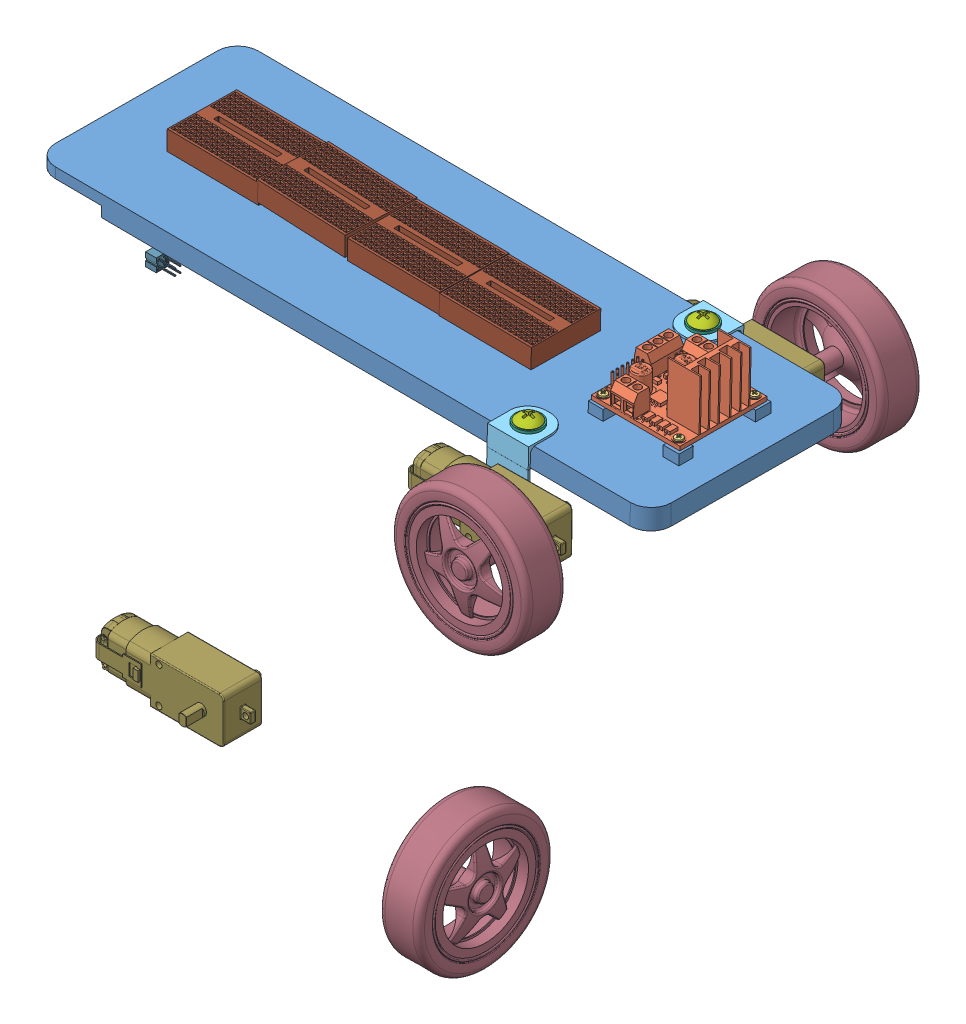
SolidWorks assembly Ensamblaje2, configuration Predeterminado. Lengths in mm.
Overall size (300.72 217.27 230.2).
39 component instances, 14 part files, 0 mates.
Components (placement in the parent):
- Ensamblaje plataforma (1)-2: Ensamblaje plataforma (1) [Default] at (-178.3649 -24.868 89.8668) size (300.72 90.29 196.84)
  - Assem2^Ensamblaje plataforma (1)-1: Assem2^Ensamblaje plataforma (1) [Default] at (0.8961 4.1073 -9.7074) x (0.999922 -0.011126 -0.00562) z (0.005746 0.011285 0.99992) size (300 15 100) (virtual)
    - Plataforma base-1: Plataforma base [Default] at (153.6211 143.2192 210.7445) size (300 15 100)
  - L298N Stepper Motor Driver (Red)-Part File_1-1: L298N Stepper Motor Driver (Red)-Part File_1 [Default] at (301.8886 161.1935 182.1116) x (0.009007 0.011249 0.999896) z (-0.999898 0.011163 0.008881) size (43 28.01 43)
  - binding head screw_ai-7: binding head screw_ai [CR-BHMS 0.073-64x0.5625x0.5625-N] at (283.2015 164.4308 163.4984) x (-0.011062 -0.999874 0.011348) z (0.010989 0.011226 0.999877) size (15.31 3.89 3.89)
  - binding head screw_ai-8: binding head screw_ai [CR-BHMS 0.073-64x0.5625x0.5625-N] at (283.5381 164.8513 200.874) x (-0.011062 -0.999874 0.011348) z (0.010989 0.011226 0.999877) size (15.31 3.89 3.89)
  - binding head screw_ai-9: binding head screw_ai [CR-BHMS 0.073-64x0.5625x0.5625-N] at (320.2762 164.4411 200.5477) x (-0.011062 -0.999874 0.011348) z (0.010989 0.011226 0.999877) size (15.31 3.89 3.89)
  - binding head screw_ai-10: binding head screw_ai [CR-BHMS 0.073-64x0.75x0.75-N] at (319.9395 164.0207 163.172) x (-0.011062 -0.999874 0.011348) z (0.010989 0.011226 0.999877) size (20.07 3.89 3.89)
  - machine screw nut hex_ai-2: machine screw nut hex_ai [MSHXNUT 0.073-64-S-N] at (283.5126 162.5402 200.9002) x (0.999878 -0.010935 0.011196) z (-0.011062 -0.999874 0.011348) size (3.96 4.58 1.27)
  - machine screw nut hex_ai-4: machine screw nut hex_ai [MSHXNUT 0.073-64-S-N] at (283.3545 148.2545 201.0623) x (0.999878 -0.010935 0.011196) z (-0.011062 -0.999874 0.011348) size (3.96 4.58 1.27)
  - machine screw nut hex_ai-5: machine screw nut hex_ai [MSHXNUT 0.073-64-S-N] at (320.5771 144.933 201.3417) x (0.999878 -0.010935 0.011196) z (-0.011062 -0.999874 0.011348) size (3.96 4.58 1.27)
  - machine screw nut hex_ai-6: machine screw nut hex_ai [MSHXNUT 0.073-64-S-N] at (319.8874 159.3099 163.2255) x (0.999878 -0.010935 0.011196) z (-0.011062 -0.999874 0.011348) size (3.96 4.58 1.27)
  - machine screw nut hex_ai-7: machine screw nut hex_ai [MSHXNUT 0.073-64-S-N] at (320.5414 144.5009 163.2339) x (0.999878 -0.010935 0.011196) z (-0.011062 -0.999874 0.011348) size (3.96 4.58 1.27)
  - machine screw nut hex_ai-8: machine screw nut hex_ai [MSHXNUT 0.073-64-S-N] at (283.0179 147.834 163.6867) x (0.999878 -0.010935 0.011196) z (-0.011062 -0.999874 0.011348) size (3.96 4.58 1.27)
  - L bracket-1: L bracket [fillet] at (261.6469 158.1935 235.7102) x (-0.011062 -0.999874 0.011348) z (0.999899 -0.011162 -0.008829) size (40 20 20)
  - L bracket-2: L bracket [fillet] at (281.5547 157.1066 130.005) x (-0.011062 -0.999874 0.011348) z (-0.999899 0.010959 -0.009033) size (40 20 20)
  - flat washer type a selected narrow_ai-3: flat washer type a selected narrow_ai [Selected Narrow FW 0.25] at (271.5589 157.969 225.5866) x (-0.011062 -0.999874 0.011348) z (-0.011352 0.011473 0.99987) size (1.24 12.7 12.7)
  - flat washer type a selected narrow_ai-4: flat washer type a selected narrow_ai [Selected Narrow FW 0.25] at (271.4634 157.3311 139.9499) x (-0.011062 -0.999874 0.011348) z (-0.011352 0.011473 0.99987) size (1.24 12.7 12.7)
  - truss head screw_ai-5: truss head screw_ai [CR-THMS 0.19-24x0.75x0.75-N] at (271.6058 162.2102 225.5385) x (-0.011062 -0.999874 0.011348) z (-0.011352 0.011473 0.99987) size (22 11.38 11.38)
  - truss head screw_ai-6: truss head screw_ai [CR-THMS 0.19-24x0.75x0.75-N] at (271.5103 161.5724 139.9017) x (-0.011062 -0.999874 0.011348) z (-0.011352 0.011473 0.99987) size (22 11.38 11.38)
  - flat washer type b regular_ai-5: flat washer type b regular_ai [Regular FW 0.086] at (271.0534 123.1538 131.3003) x (0.008908 -0.011447 -0.999895) z (0.999895 -0.011344 0.009038) size (0.81 6.35 6.35)
  - flat washer type b regular_ai-6: flat washer type b regular_ai [Regular FW 0.086] at (271.2548 141.3595 131.0936) x (0.008908 -0.011447 -0.999895) z (0.999895 -0.011344 0.009038) size (0.81 6.35 6.35)
  - flat washer type b wide_ai-3: flat washer type b wide_ai [Wide FW 0.086] at (273.918 141.0664 234.8581) x (0.008955 0.011258 0.999897) z (-0.999897 -0.011157 0.00908) size (0.81 8.74 8.74)
  - flat washer type b wide_ai-4: flat washer type b wide_ai [Wide FW 0.086] at (271.376 123.9939 234.9722) x (0.008954 0.011249 0.999897) z (-0.999897 -0.011157 0.00908) size (0.81 8.74 8.74)
  - hex jam nut_ai-2: hex jam nut_ai [HJNUT 0.2500-20-D-N] at (271.392 142.8837 225.7578) x (0.999884 -0.010942 0.010586) z (-0.011062 -0.999874 0.011348) size (11.11 12.83 4.14)
  - hex jam nut_ai-3: hex jam nut_ai [HJNUT 0.2500-20-D-N] at (271.2928 141.9129 140.1249) x (0.999884 -0.010942 0.010586) z (-0.011062 -0.999874 0.011348) size (11.11 12.83 4.14)
  - MINIPROTOBOARD-1: MINIPROTOBOARD [Default] at (181.0501 157.9729 184.2797) x (0.999939 -0.011067 -0.000394) z (0.000519 0.011343 0.999936) size (45 9.5 34)
  - MINIPROTOBOARD-2: MINIPROTOBOARD [Default] at (226.0349 157.0566 184.277) x (0.999939 -0.011062 0.000066) z (0.00006 0.011348 0.999936) size (45 9.5 34)
  - MINIPROTOBOARD-3: MINIPROTOBOARD [Default] at (135.4578 159.1036 183.4633) x (0.9993 -0.010648 0.035871) z (-0.035745 0.011737 0.999292) size (45 9.5 34)
  - MINIPROTOBOARD-4: MINIPROTOBOARD [Default] at (91.072 158.5316 182.6776) x (0.999939 -0.011062 0.000066) z (0.00006 0.011348 0.999936) size (45 9.5 34)
  - Moto Reductor - Rueda-1: Moto Reductor - Rueda [Predeterminado] at (332.7726 136.1213 57.1191) x (0.99996 0.000051 0.008908) z (-0.008908 0.011447 0.999895) size (86.5 66 53.9)
    - Moto Reductor 01-1: Moto Reductor 01 [Predeterminado] at (-77.2566 -5.0689 64.1747) size (69.7 22.5 36.8)
    - Rueda 01-2: Rueda 01 [Predeterminado] at (-40.4566 -5.0689 48.6747) x (0 0 -1) z (1 0 0) size (25 66 66)
  - Moto Reductor - Rueda-2: Moto Reductor - Rueda [Predeterminado] at (333.0983 128.5086 308.9866) x (0.99996 -0.000089 -0.008954) z (-0.008954 -0.011249 -0.999897) size (86.5 66 53.9)
    - Moto Reductor 01-1: Moto Reductor 01 [Predeterminado] at (-77.2566 -5.0689 64.1747) size (69.7 22.5 36.8)
    - Rueda 01-2: Rueda 01 [Predeterminado] at (-40.4566 -5.0689 48.6747) x (0 0 -1) z (1 0 0) size (25 66 66)
- Rueda 01-2: Rueda 01 [Predeterminado] at (109.0089 -20.4692 371.7006) size (25 66 66)
- Moto Reductor 01-2: Moto Reductor 01 [Predeterminado] at (-33.4097 2.1113 376.6152) size (69.7 22.5 36.8)
- CNY70-1: CNY70 [Predeterminado] at (-97.2543 106.0342 309.3574) size (12.75 6.3 6.3)
